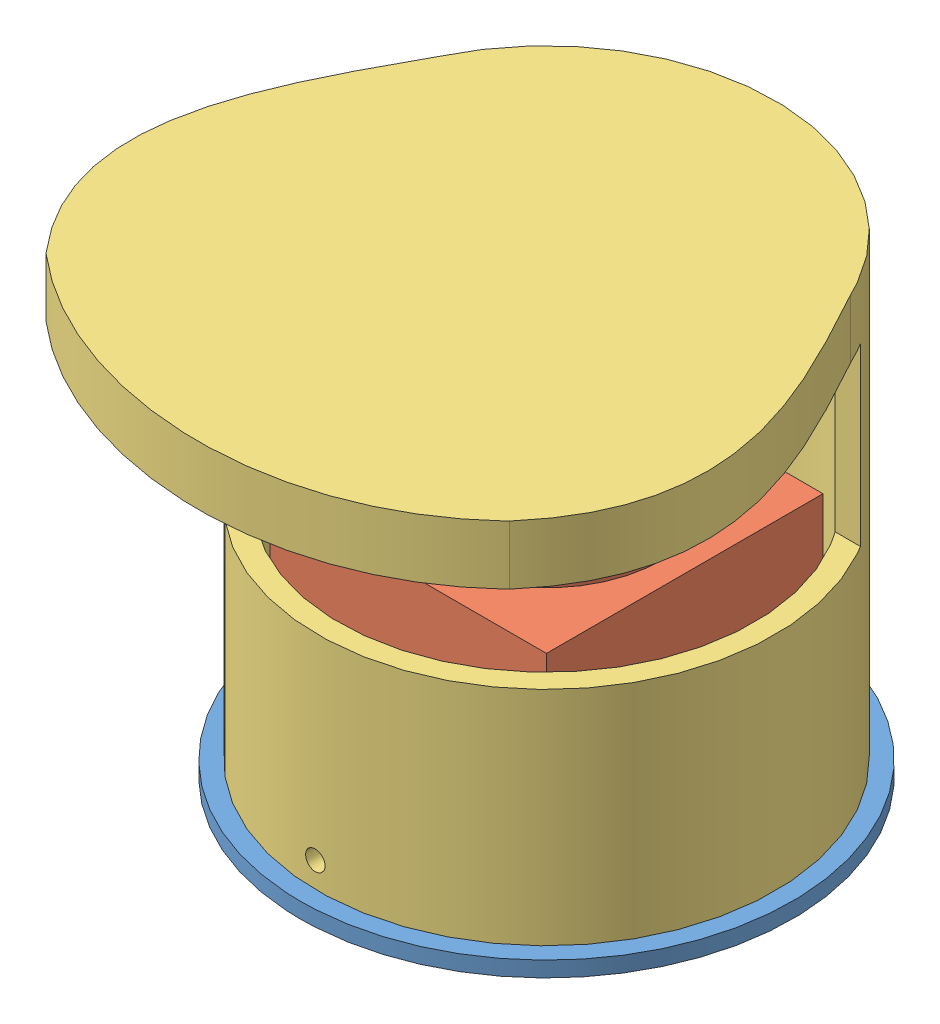
SolidWorks assembly LIDAR_case, configuration Default. Lengths in mm.
Overall size (128.27 85.36 108.59).
3 component instances, 3 part files, 8 mates.
Components (placement in the parent):
- LIDAR_base-1: LIDAR_base [Default] at origin size (88.9 11.68 88.9)
- LIDAR-1: LIDAR [Default] at (19.45 3.0942 -69.45) size (50 70.6 50)
- LIDAR_top-1: LIDAR_top [Default] at (44.45 2.794 -44.45) x (0 0 -1) z (1 0 0) size (105.42 82.56 128.27)
Mates (geometry in assembly coordinates):
- Coincident1: coincident aligned: plane of LIDAR_base-1 through (0 0 0) normal (0 0 1)
- Coincident2: coincident aligned: plane of LIDAR_base-1 through (0 0 0) normal (0 1 0)
- Coincident3: coincident aligned: plane of LIDAR_base-1 through (0 0 0) normal (1 0 0)
- Coincident14: coincident anti-aligned: plane of LIDAR-1 through (19.45 3.0942 -44.45) normal (0 0 1); plane of LIDAR_top-1 through (44.45 2.794 -44.45) normal (0 0 -1)
- Coincident15: coincident aligned: plane of LIDAR-1 through (44.45 3.0942 -69.45) normal (1 0 0); plane of LIDAR_top-1 through (44.45 2.794 -44.45) normal (1 0 0)
- Concentric1: concentric aligned: cylinder of LIDAR_base-1 through (65.314 2.794 -23.586) axis (0 -1 0) radius 1.7; cylinder of LIDAR-1 through (65.314 15.7942 -23.586) axis (0 -1 0) radius 1.7
- Concentric2: concentric aligned: cylinder of LIDAR_base-1 through (23.586 2.794 -65.314) axis (0 -1 0) radius 1.7; cylinder of LIDAR-1 through (23.586 15.7942 -65.314) axis (0 -1 0) radius 1.7
- Coincident16: coincident anti-aligned: plane of LIDAR_base-1 through (44.45 2.794 -44.45) normal (0 1 0); plane of LIDAR_top-1 through (44.45 2.794 -44.45) normal (0 -1 0)
